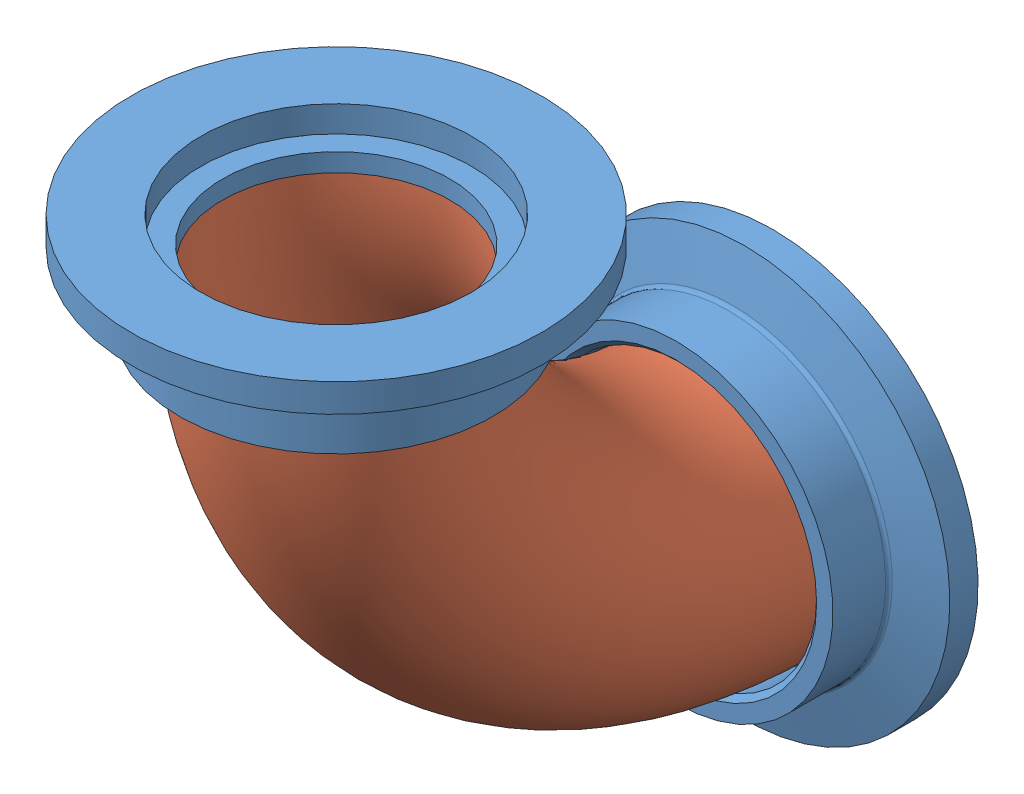
SolidWorks assembly 723019, configuration Default. Lengths in mm.
Overall size (48.62 62.36 66.73).
3 component instances, 2 part files, 8 mates.
Components (placement in the parent):
- 972301-1: 972301 [Default] x (0 0 1) z (0 1 0) size (9.4 39.88 39.88)
- 403541-1: 403541 [Default] at (0 0 4.318) size (25.4 50.8 50.8)
- 972301-2: 972301 [Default] at (0 42.418 42.418) x (0 -1 0) z (0.251399 0 -0.967884) size (9.4 39.88 39.88)
Mates (geometry in assembly coordinates):
- Coincident1: coincident aligned: plane of 972301-1 through (0 0 0) normal (0 0 1)
- Coincident2: coincident aligned: plane of 972301-1 through (0 0 0) normal (0 1 0)
- Coincident3: coincident aligned: plane of 972301-1 through (0 0 0) normal (1 0 0)
- Concentric1: concentric aligned: circle of 972301-1; circle of 403541-1
- Coincident4: coincident anti-aligned: plane of 972301-1 through (11.049 0 4.318) normal (0 0 1); plane of 403541-1 through (0 0 4.318) normal (0 0 -1)
- Coincident5: coincident aligned: plane of 403541-1 through (0 0 4.318) normal (1 0 0)
- Concentric2: concentric anti-aligned: circle of 403541-1; circle of 972301-2
- Coincident6: coincident anti-aligned: plane of 403541-1 through (0 38.1 42.418) normal (0 1 0); plane of 972301-2 through (-10.6941 38.1 39.6403) normal (0 -1 0)
